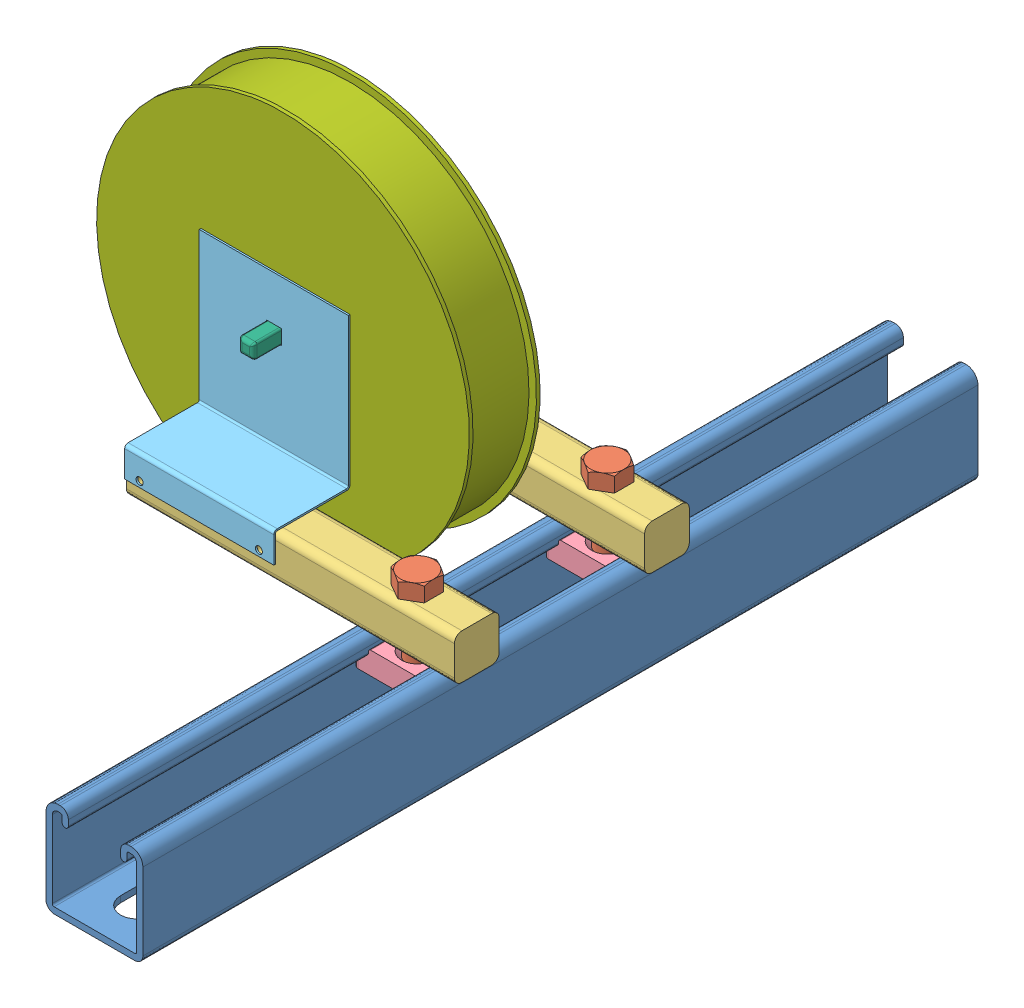
SolidWorks assembly Lower Outer Pulley System, configuration Default. Lengths in mm.
Overall size (195.6 189.99 355.6).
11 component instances, 7 part files, 29 mates.
Components (placement in the parent):
- P1000T - Unistrut Channel (Slots)-1: P1000T - Unistrut Channel (Slots) [1'-2"] at (233.0175 285.7278 699.4321) size (41.28 41.27 355.6)
- hex bolt_ai-1: hex bolt_ai [HBOLT 0.3750-24x1.5x1-C] at (233.1269 332.2224 481.1508) x (0 -1 0) z (0.5 0 0.866025) size (44.91 16.48 14.27)
- Supporting Rod-1: Supporting Rod [Default] at (118.8269 315.8902 481.1508) size (139.7 19.05 19.05)
- P3013 - Channel Nut-1: P3013 - Channel Nut [.375"] at (233.1269 302.0059 481.1508) x (1 0 0) z (0 1 0) size (34.99 19.63 9.53)
- Lower Outer Bracket-1: Lower Outer Bracket [Default] at (182.3269 335.259 499.7984) x (-1 0 0) z (0 0 -1) size (63.5 76.2 32.49)
- Lower Outer Pin-1: Lower Outer Pin [Default] at (150.5769 367.4268 521.6321) x (0 0 1) z (-1 0 0) size (61.91 6.45 6.45)
- Wide Pulley-1: Wide Pulley [6"x0.25"] at (150.5769 367.4268 521.6321) x (-0.110425 0.993884 0) z (0 0 1) size (158.75 158.75 30.16)
- hex bolt_ai-2: hex bolt_ai [HBOLT 0.3750-24x1.5x1-C] at (233.1269 332.2224 562.1133) x (0 -1 0) z (0.5 0 0.866025) size (44.91 16.48 14.27)
- Supporting Rod-3: Supporting Rod [Default] at (118.8269 315.8902 562.1133) size (139.7 19.05 19.05)
- P3013 - Channel Nut-3: P3013 - Channel Nut [.375"] at (233.1269 302.0059 562.1133) x (1 0 0) z (0 1 0) size (34.99 19.63 9.53)
- Lower Outer Bracket-2: Lower Outer Bracket [Default] at (118.8269 335.259 543.4657) size (63.5 76.2 32.49)
Mates (geometry in assembly coordinates):
- Coincident1: coincident anti-aligned: plane of P1000T - Unistrut Channel (Slots)-1 through (221.9048 300.5612 343.8321) normal (1 0 0); plane of P3013 - Channel Nut-1 through (221.9048 302.0059 490.6759) normal (-1 0 0)
- Tangent3: tangent anti-aligned: cylinder of P1000T - Unistrut Channel (Slots)-1 through (220.5713 300.5612 343.8321) axis (0 0 1) radius 1.3335; plane of P3013 - Channel Nut-1 through (221.1 299.2277 490.6759) normal (0 1 0)
- Concentric1: concentric aligned: cylinder of hex bolt_ai-1 through (233.1269 332.2224 481.1508) axis (0 1 0) radius 4.7625; cylinder of Supporting Rod-1 through (233.1269 306.3652 481.1508) axis (0 1 0) radius 4.7625
- Concentric2: concentric aligned: cylinder of hex bolt_ai-1 through (233.1269 332.2224 481.1508) axis (0 1 0) radius 4.7625; cylinder of P3013 - Channel Nut-1 through (233.1269 302.0059 481.1508) axis (0 1 0) radius 4.7625
- Parallel1: parallel aligned: plane of P1000T - Unistrut Channel (Slots)-1 through (253.6552 301.3169 343.8321) normal (1 0 0); plane of hex bolt_ai-1 through (240.2643 325.4152 477.03) normal (1 0 0)
- Coincident3: coincident anti-aligned: plane of P1000T - Unistrut Channel (Slots)-1 through (247.5909 306.3652 343.8321) normal (0 1 0); plane of Supporting Rod-1 through (258.5269 306.3652 490.6758) normal (0 -1 0)
- Coincident4: coincident anti-aligned: plane of hex bolt_ai-1 through (240.2643 325.4152 477.03) normal (0 -1 0); plane of Supporting Rod-1 through (258.5269 325.4152 490.6758) normal (0 1 0)
- Parallel2: parallel aligned: plane of P1000T - Unistrut Channel (Slots)-1 through (253.6552 301.3169 343.8321) normal (1 0 0); plane of Supporting Rod-1 through (258.5269 315.8902 481.1508) normal (1 0 0)
- Concentric3: concentric anti-aligned: cylinder of Supporting Rod-1 through (175.9769 315.8902 471.6258) axis (0 0 1) radius 1.5; cylinder of Lower Outer Bracket-1 through (175.9769 315.8902 503.3758) axis (0 0 -1) radius 1.5
- Concentric4: concentric anti-aligned: cylinder of Supporting Rod-1 through (125.1769 315.8902 471.6258) axis (0 0 1) radius 1.5; cylinder of Lower Outer Bracket-1 through (125.1769 315.8902 503.3758) axis (0 0 -1) radius 1.5
- Coincident6: coincident anti-aligned: plane of Supporting Rod-1 through (258.5269 306.3652 471.6258) normal (0 0 -1); plane of Lower Outer Bracket-1 through (118.8269 313.4518 471.6258) normal (0 0 1)
- Coincident7: coincident anti-aligned: plane of Lower Outer Bracket-1 through (153.7519 370.6018 503.3758) normal (0 -1 0); plane of Lower Outer Pin-1 through (147.4019 370.6018 481.6956) normal (0 1 0)
- Coincident8: coincident anti-aligned: plane of Lower Outer Bracket-1 through (147.4019 364.2518 503.3758) normal (1 0 0); plane of Lower Outer Pin-1 through (147.4019 364.2518 481.6956) normal (-1 0 0)
- Concentric5: concentric aligned: cylinder of Lower Outer Pin-1 through (150.5769 367.4268 512.6518) axis (0 0 1) radius 3.175; cylinder of Wide Pulley-1 through (150.5769 367.4268 506.5508) axis (0 0 1) radius 3.175
- Coincident9: coincident aligned: circle of Lower Outer Pin-1; circle of Wide Pulley-1
- Coincident10: coincident anti-aligned: line of Lower Outer Bracket-1 through (153.7519 370.6018 503.3758) axis (0 -1 0); line of Lower Outer Pin-1 through (153.7519 365.0455 503.3758) axis (0 1 0)
- Coincident11: coincident anti-aligned: plane of P1000T - Unistrut Channel (Slots)-1 through (221.9048 300.5612 343.8321) normal (1 0 0); plane of P3013 - Channel Nut-3 through (221.9048 302.0059 571.6384) normal (-1 0 0)
- Tangent4: tangent anti-aligned: cylinder of P1000T - Unistrut Channel (Slots)-1 through (220.5713 300.5612 343.8321) axis (0 0 1) radius 1.3335; plane of P3013 - Channel Nut-3 through (221.1 299.2277 571.6384) normal (0 1 0)
- Concentric6: concentric aligned: cylinder of hex bolt_ai-2 through (233.1269 332.2224 562.1133) axis (0 1 0) radius 4.7625; cylinder of Supporting Rod-3 through (233.1269 306.3652 562.1133) axis (0 1 0) radius 4.7625
- Concentric7: concentric aligned: cylinder of hex bolt_ai-2 through (233.1269 332.2224 562.1133) axis (0 1 0) radius 4.7625; cylinder of P3013 - Channel Nut-3 through (233.1269 302.0059 562.1133) axis (0 1 0) radius 4.7625
- Coincident12: coincident anti-aligned: plane of P1000T - Unistrut Channel (Slots)-1 through (247.5909 306.3652 343.8321) normal (0 1 0); plane of Supporting Rod-3 through (258.5269 306.3652 571.6383) normal (0 -1 0)
- Coincident13: coincident anti-aligned: plane of hex bolt_ai-2 through (240.2643 325.4152 557.9925) normal (0 -1 0); plane of Supporting Rod-3 through (258.5269 325.4152 571.6383) normal (0 1 0)
- Parallel3: parallel aligned: plane of P1000T - Unistrut Channel (Slots)-1 through (253.6552 301.3169 343.8321) normal (1 0 0); plane of Supporting Rod-3 through (258.5269 315.8902 562.1133) normal (1 0 0)
- Concentric8: concentric aligned: cylinder of Supporting Rod-3 through (175.9769 315.8902 552.5883) axis (0 0 1) radius 1.5; cylinder of Lower Outer Bracket-2 through (175.9769 315.8902 539.8883) axis (0 0 1) radius 1.5
- Concentric9: concentric aligned: cylinder of Supporting Rod-3 through (125.1769 315.8902 552.5883) axis (0 0 1) radius 1.5; cylinder of Lower Outer Bracket-2 through (125.1769 315.8902 539.8883) axis (0 0 1) radius 1.5
- Coincident14: coincident anti-aligned: plane of Supporting Rod-3 through (258.5269 306.3652 571.6383) normal (0 0 1); plane of Lower Outer Bracket-2 through (182.3269 313.4518 571.6383) normal (0 0 -1)
- Coincident15: coincident aligned: line of Lower Outer Pin-1 through (147.4019 369.808 539.8883) axis (0 -1 0); line of Lower Outer Bracket-2 through (147.4019 370.6018 539.8883) axis (0 -1 0)
- Symmetric1: symmetric aligned: plane of Wide Pulley-1 through (150.5769 367.4268 536.7133) normal (0 0 1); plane of Wide Pulley-1 through (150.5769 367.4268 506.5508) normal (0 0 -1); plane of assembly through (0 0 521.6321) normal (0 0 1)
- Parallel4: parallel aligned: plane of P1000T - Unistrut Channel (Slots)-1 through (253.6552 301.3169 343.8321) normal (1 0 0); plane of hex bolt_ai-2 through (240.2643 325.4152 557.9925) normal (1 0 0)
